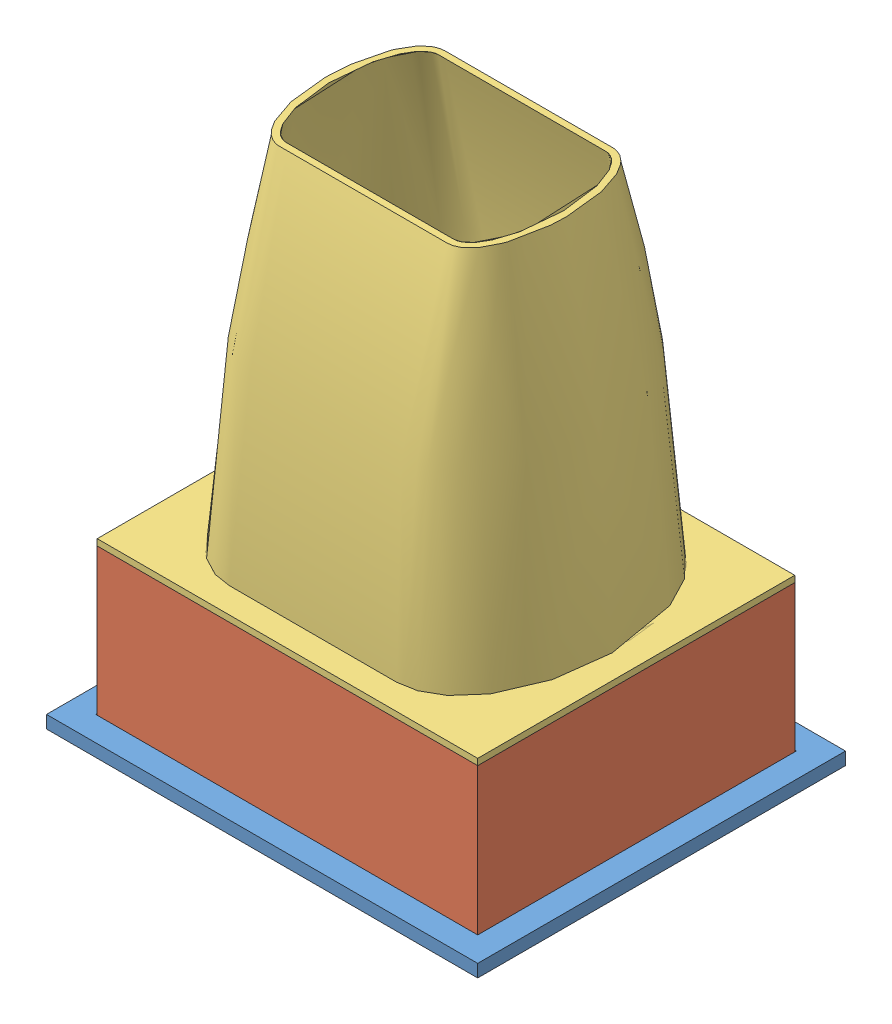
SolidWorks assembly Base Assembly Arduino, configuration Default. Lengths in mm.
Overall size (170 85.37 145).
4 component instances, 4 part files, 9 mates.
Components (placement in the parent):
- Base Bottom Arduino-2: Base Bottom Arduino [Default] at (57.5585 73.6731 141.2736) x (-1 0 0) z (0 0 -1) size (170 26.5 145)
- Base Middle Arduino-1: Base Middle Arduino [Default] at (57.5585 76.1731 141.2736) size (150 60 125)
- Base Top Arduino-1: Base Top Arduino [Default] at (57.5585 138.6731 141.2736) x (-1 0 0) z (0 0 -1) size (150 142.51 125)
- Perfboard-1: Perfboard [Default] at (92.5585 96.1731 171.5736) x (0 0 -1) z (1 0 0) size (90 1.5 70)
Mates (geometry in assembly coordinates):
- Coincident1: coincident anti-aligned: plane of Base Bottom Arduino-2 through (57.5585 76.1731 141.2736) normal (0 1 0); plane of Base Middle-1 through (57.5585 76.1731 141.2736) normal (0 -1 0)
- Distance1: distance = 0.3 mm anti-aligned: plane of Base Bottom Arduino-2 through (132.8585 76.1731 204.0736) normal (0 0 -1); plane of Base Middle Arduino-1 through (57.5585 136.1731 203.7736) normal (0 0 1)
- Distance2: distance = 0.3 mm anti-aligned: plane of Base Bottom Arduino-2 through (-17.7415 76.1731 78.4736) normal (1 0 0); plane of Base Middle Arduino-1 through (-17.4415 136.1731 141.2736) normal (-1 0 0)
- Coincident4: coincident anti-aligned: plane of Base Middle-1 through (57.5585 136.1731 141.2736) normal (0 1 0); plane of Base Top-1 through (57.5585 136.1731 141.2736) normal (0 -1 0)
- Coincident5: coincident aligned: plane of Base Middle-1 through (57.5585 136.1731 203.7736) normal (0 0 1); plane of Base Top-1 through (132.5585 136.1731 203.7736) normal (0 0 1)
- Coincident6: coincident aligned: plane of Base Middle-1 through (-17.4415 136.1731 141.2736) normal (-1 0 0); plane of Base Top-1 through (-17.4415 136.1731 78.7736) normal (-1 0 0)
- Coincident7: coincident anti-aligned: plane of Base Bottom Arduino-2 through (57.5585 96.1731 141.2736) normal (0 1 0); plane of Perfboard-1 through (92.5585 96.1731 171.5736) normal (0 -1 0)
- Coincident8: coincident anti-aligned: plane of Base Bottom Arduino-2 through (22.0585 100.1731 171.5736) normal (0 0 -1); plane of Perfboard-1 through (92.5585 97.6731 171.5736) normal (0 0 1)
- Distance3: distance = 0.5 mm anti-aligned: plane of Base Bottom Arduino-2 through (93.0585 100.1731 166.5736) normal (-1 0 0); plane of Perfboard-1 through (92.5585 97.6731 171.5736) normal (1 0 0)
